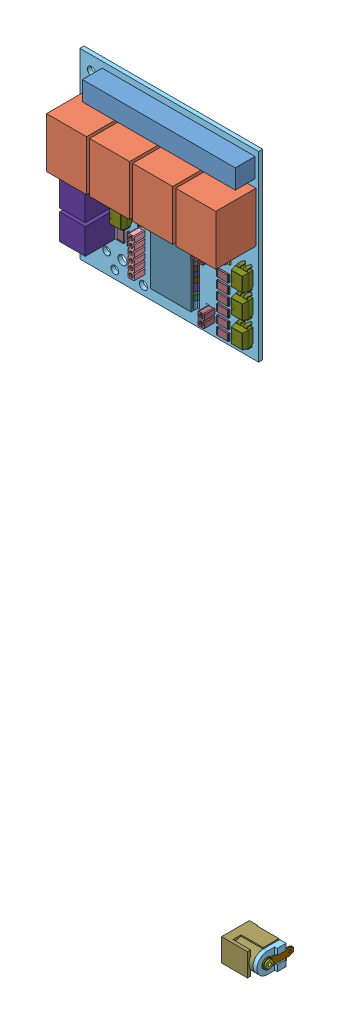
SolidWorks assembly wifi_switch, configuration Default. Lengths in mm.
Overall size (288.45 72 221.81).
193 component instances, 59 part files, 0 mates.
Components (placement in the parent):
- wifi_switch.STEP-1: wifi_switch.STEP [Default] at origin size (288.45 72 221.81)
  - 8PIN_TERMINAL.STEP-1: 8PIN_TERMINAL.STEP [Default] at (-41 33.5 0.803) size (60.33 7.62 11.71)
    - Open CASCADE STEP translator 6.8 1.2.1.STEP-1: Open CASCADE STEP translator 6.8 1.2.1.STEP [Default] at origin size (60.33 7.62 11.71)
      - Body_1.STEP-1: Body_1.STEP [Default] at origin size (60.33 7.62 7.8)
      - Pin_1.STEP-1: Pin_1.STEP [Default] x (0 -1 0) z (0 0 1) size (1.42 1.42 8.52)
      - Pin_2.STEP-1: Pin_2.STEP [Default] at (5.0038 5.0038 0) x (0 -1 0) z (0 0 1) size (1.42 1.42 8.52)
      - Pin_3.STEP-1: Pin_3.STEP [Default] at (10.0076 10.0076 0) x (0 -1 0) z (0 0 1) size (1.42 1.42 8.52)
      - Pin_4.STEP-1: Pin_4.STEP [Default] at (15.0114 15.0114 0) x (0 -1 0) z (0 0 1) size (1.42 1.42 8.52)
      - Pin_5.STEP-1: Pin_5.STEP [Default] at (19.9898 19.9898 0) x (0 -1 0) z (0 0 1) size (1.42 1.42 8.52)
      - Pin_6.STEP-1: Pin_6.STEP [Default] at (24.9936 24.9936 0) x (0 -1 0) z (0 0 1) size (1.42 1.42 8.52)
      - Pin_7.STEP-1: Pin_7.STEP [Default] at (29.9974 29.9974 0) x (0 -1 0) z (0 0 1) size (1.42 1.42 8.52)
      - Pin_8.STEP-1: Pin_8.STEP [Default] at (35.0012 35.0012 0) x (0 -1 0) z (0 0 1) size (1.42 1.42 8.52)
      - Pin_9.STEP-1: Pin_9.STEP [Default] at (40.005 40.005 0) x (0 -1 0) z (0 0 1) size (1.42 1.42 8.52)
      - Pin_10.STEP-1: Pin_10.STEP [Default] at (45.0088 45.0088 0) x (0 -1 0) z (0 0 1) size (1.42 1.42 8.52)
      - Pin_11.STEP-1: Pin_11.STEP [Default] at (50.0126 50.0126 0) x (0 -1 0) z (0 0 1) size (1.42 1.42 8.52)
      - Pin_12.STEP-1: Pin_12.STEP [Default] at (54.991 54.991 0) x (0 -1 0) z (0 0 1) size (1.42 1.42 8.52)
  - ESP.STEP-1: ESP.STEP [Default] at (-5.5 -10.5 0.803) size (18.25 24 2.16)
    - Open CASCADE STEP translator 6.8 1.3.1.STEP-1: Open CASCADE STEP translator 6.8 1.3.1.STEP [Default] at origin size (18.25 24 2.16)
      - Body_1-0.STEP-1: Body_1-0.STEP [Default] at origin size (16 24 1.91)
      - Pin_1-1.STEP-1: Pin_1-1.STEP [Default] at origin size (1.12 2.9 1.33)
      - Pin_2-2.STEP-1: Pin_2-2.STEP [Default] at origin size (1.12 2.9 1.33)
      - Pin_3-3.STEP-1: Pin_3-3.STEP [Default] at origin size (1.12 2.9 1.33)
      - Pin_4-4.STEP-1: Pin_4-4.STEP [Default] at origin size (1.12 2.9 1.33)
      - Pin_5-5.STEP-1: Pin_5-5.STEP [Default] at origin size (1.12 2.9 1.33)
      - Pin_6-6.STEP-1: Pin_6-6.STEP [Default] at origin size (1.12 2.9 1.33)
      - Pin_7-7.STEP-1: Pin_7-7.STEP [Default] at origin size (1.12 2.9 1.33)
      - Pin_8-8.STEP-1: Pin_8-8.STEP [Default] at origin size (1.12 2.9 1.33)
      - Pin_9-9.STEP-1: Pin_9-9.STEP [Default] at (0 -28 0) x (-1 0 0) z (0 0 1) size (1.13 2.9 1.33)
      - Pin_10-10.STEP-1: Pin_10-10.STEP [Default] at (0 -24 0) x (-1 0 0) z (0 0 1) size (1.13 2.9 1.33)
      - Pin_11-11.STEP-1: Pin_11-11.STEP [Default] at (0 -20 0) x (-1 0 0) z (0 0 1) size (1.13 2.9 1.33)
      - Pin_12-12.STEP-1: Pin_12-12.STEP [Default] at (0 -16 0) x (-1 0 0) z (0 0 1) size (1.13 2.9 1.33)
      - Pin_13.STEP-1: Pin_13.STEP [Default] at (0 -12 0) x (-1 0 0) z (0 0 1) size (1.13 2.9 1.33)
      - Pin_14.STEP-1: Pin_14.STEP [Default] at (0 -8 0) x (-1 0 0) z (0 0 1) size (1.13 2.9 1.33)
      - Pin_15.STEP-1: Pin_15.STEP [Default] at (0 -4 0) x (-1 0 0) z (0 0 1) size (1.13 2.9 1.33)
      - Pin_16.STEP-1: Pin_16.STEP [Default] x (-1 0 0) z (0 0 1) size (1.13 2.9 1.33)
  - R1_470.STEP-1: R1_470.STEP [Default] at (-36 -18 0.803) x (0 1 0) z (0 0 1) size (4.78 2.7 0.65)
    - Open CASCADE STEP translator 6.8 1.4.1.STEP-1: Open CASCADE STEP translator 6.8 1.4.1.STEP [Default] at origin size (4.78 2.7 0.65)
      - Body_1-13.STEP-1: Body_1-13.STEP [Default] at origin size (4.4 2.68 0.63)
      - Pin_1-14.STEP-1: Pin_1-14.STEP [Default] at (0.374 0 0) x (-1 0 0) z (0 0 1) size (0.45 2.7 0.65)
      - Pin_2-15.STEP-1: Pin_2-15.STEP [Default] at origin size (0.45 2.7 0.65)
  - R3_470.STEP-1: R3_470.STEP [Default] at (2 -9.5 0.803) size (4.78 2.7 0.65)
    - Open CASCADE STEP translator 6.8 1.4.1.STEP-1: Open CASCADE STEP translator 6.8 1.4.1.STEP [Default] at origin size (4.78 2.7 0.65)
      - Body_1-13.STEP-1: Body_1-13.STEP [Default] at origin size (4.4 2.68 0.63)
      - Pin_1-14.STEP-1: Pin_1-14.STEP [Default] at (0.374 0 0) x (-1 0 0) z (0 0 1) size (0.45 2.7 0.65)
      - Pin_2-15.STEP-1: Pin_2-15.STEP [Default] at origin size (0.45 2.7 0.65)
  - R5_470.STEP-1: R5_470.STEP [Default] at (2 -13.5 0.803) size (4.78 2.7 0.65)
    - Open CASCADE STEP translator 6.8 1.4.1.STEP-1: Open CASCADE STEP translator 6.8 1.4.1.STEP [Default] at origin size (4.78 2.7 0.65)
      - Body_1-13.STEP-1: Body_1-13.STEP [Default] at origin size (4.4 2.68 0.63)
      - Pin_1-14.STEP-1: Pin_1-14.STEP [Default] at (0.374 0 0) x (-1 0 0) z (0 0 1) size (0.45 2.7 0.65)
      - Pin_2-15.STEP-1: Pin_2-15.STEP [Default] at origin size (0.45 2.7 0.65)
  - R7_470.STEP-1: R7_470.STEP [Default] at (2 -17.5 0.803) size (4.78 2.7 0.65)
    - Open CASCADE STEP translator 6.8 1.4.1.STEP-1: Open CASCADE STEP translator 6.8 1.4.1.STEP [Default] at origin size (4.78 2.7 0.65)
      - Body_1-13.STEP-1: Body_1-13.STEP [Default] at origin size (4.4 2.68 0.63)
      - Pin_1-14.STEP-1: Pin_1-14.STEP [Default] at (0.374 0 0) x (-1 0 0) z (0 0 1) size (0.45 2.7 0.65)
      - Pin_2-15.STEP-1: Pin_2-15.STEP [Default] at origin size (0.45 2.7 0.65)
  - OP1.STEP-1: OP1.STEP [Default] at (-35.5 -11 0.803) size (5.08 7.92 7.75)
    - Open CASCADE STEP translator 6.8 1.8.1.STEP-1: Open CASCADE STEP translator 6.8 1.8.1.STEP [Default] at origin size (5.08 7.92 7.75)
      - Body_1-16.STEP-1: Body_1-16.STEP [Default] at (1.3 3.7 0) x (0 1 0) z (1 0 0) size (7.92 7.75 5.08)
  - OP2.STEP-1: OP2.STEP [Default] at (12.5 -8.5 0.803) size (5.08 7.92 7.75)
    - Open CASCADE STEP translator 6.8 1.9.1.STEP-1: Open CASCADE STEP translator 6.8 1.9.1.STEP [Default] at origin size (5.08 7.92 7.75)
      - Body_1-16.STEP-1: Body_1-16.STEP [Default] at (1.3 3.7 0) x (0 1 0) z (1 0 0) size (7.92 7.75 5.08)
  - OP3.STEP-1: OP3.STEP [Default] at (12.5 -18 0.803) size (5.08 7.92 7.75)
    - Open CASCADE STEP translator 6.8 1.10.1.STEP-1: Open CASCADE STEP translator 6.8 1.10.1.STEP [Default] at origin size (5.08 7.92 7.75)
      - Body_1-16.STEP-1: Body_1-16.STEP [Default] at (1.3 3.7 0) x (0 1 0) z (1 0 0) size (7.92 7.75 5.08)
  - OP4.STEP-1: OP4.STEP [Default] at (12.5 -28 0.803) size (5.08 7.92 7.75)
    - Open CASCADE STEP translator 6.8 1.11.1.STEP-1: Open CASCADE STEP translator 6.8 1.11.1.STEP [Default] at origin size (5.08 7.92 7.75)
      - Body_1-16.STEP-1: Body_1-16.STEP [Default] at (1.3 3.7 0) x (0 1 0) z (1 0 0) size (7.92 7.75 5.08)
  - SMPS_5V_GND.STEP-1: SMPS_5V_GND.STEP [Default] at (-43.5 -4.5 0.803) x (0 1 0) z (0 0 1) size (10.16 10.16 15.71)
    - Open CASCADE STEP translator 6.8 1.12.1.STEP-1: Open CASCADE STEP translator 6.8 1.12.1.STEP [Default] at origin size (10.16 10.16 15.71)
      - Body_1-17.STEP-1: Body_1-17.STEP [Default] at origin size (10.16 10.16 11.8)
      - Pin_1-18.STEP-1: Pin_1-18.STEP [Default] x (0 -1 0) z (0 0 1) size (1.42 1.42 10.52)
      - Pin_2-19.STEP-1: Pin_2-19.STEP [Default] at (5.08 5.08 0) x (0 -1 0) z (0 0 1) size (1.42 1.42 10.52)
  - SMPS_L_N.STEP-1: SMPS_L_N.STEP [Default] at (-43.5 -16 0.803) x (0 1 0) z (0 0 1) size (10.16 10.16 15.71)
    - Open CASCADE STEP translator 6.8 1.12.1.STEP-1: Open CASCADE STEP translator 6.8 1.12.1.STEP [Default] at origin size (10.16 10.16 15.71)
      - Body_1-17.STEP-1: Body_1-17.STEP [Default] at origin size (10.16 10.16 11.8)
      - Pin_1-18.STEP-1: Pin_1-18.STEP [Default] x (0 -1 0) z (0 0 1) size (1.42 1.42 10.52)
      - Pin_2-19.STEP-1: Pin_2-19.STEP [Default] at (5.08 5.08 0) x (0 -1 0) z (0 0 1) size (1.42 1.42 10.52)
  - RL4.STEP-1: RL4.STEP [Default] at (-31 10 0.803) x (0 1 0) z (0 0 1) size (19.8 15.8 19.1)
    - Open CASCADE STEP translator 6.8 1.14.1.STEP-1: Open CASCADE STEP translator 6.8 1.14.1.STEP [Default] at origin size (19.8 15.8 19.1)
      - Body_1-20.STEP-1: Body_1-20.STEP [Default] at (6.5 -6 0) x (1 0 0) z (0 -1 0) size (19.8 19.1 15.8)
        - 1.STEP-1: 1.STEP [Default] at origin size (19.8 19.1 15.8)
        - 2.STEP-1: 2.STEP [Default] at origin size (1 4 0.4)
  - RL1.STEP-1: RL1.STEP [Default] at (-48 10 0.803) x (0 1 0) z (0 0 1) size (19.8 15.8 19.1)
    - Open CASCADE STEP translator 6.8 1.15.1.STEP-1: Open CASCADE STEP translator 6.8 1.15.1.STEP [Default] at origin size (19.8 15.8 19.1)
      - Body_1-1.STEP-1: Body_1-1.STEP [Default] at (6.5 -6 0) x (1 0 0) z (0 -1 0) size (19.8 19.1 15.8)
        - 1.STEP-1: 1.STEP [Default] at origin size (19.8 19.1 15.8)
        - 2.STEP-1: 2.STEP [Default] at origin size (1 4 0.4)
  - RL2.STEP-1: RL2.STEP [Default] at (-14 10 0.803) x (0 1 0) z (0 0 1) size (19.8 15.8 19.1)
    - Open CASCADE STEP translator 6.8 1.16.1.STEP-1: Open CASCADE STEP translator 6.8 1.16.1.STEP [Default] at origin size (19.8 15.8 19.1)
      - Body_1-2.STEP-1: Body_1-2.STEP [Default] at (6.5 -6 0) x (1 0 0) z (0 -1 0) size (19.8 19.1 15.8)
        - 1.STEP-1: 1.STEP [Default] at origin size (19.8 19.1 15.8)
        - 2.STEP-1: 2.STEP [Default] at origin size (1 4 0.4)
  - RL3.STEP-1: RL3.STEP [Default] at (3 10 0.803) x (0 1 0) z (0 0 1) size (19.8 15.8 19.1)
    - Open CASCADE STEP translator 6.8 1.17.1.STEP-1: Open CASCADE STEP translator 6.8 1.17.1.STEP [Default] at origin size (19.8 15.8 19.1)
      - Body_1-3.STEP-1: Body_1-3.STEP [Default] at (6.5 -6 0) x (1 0 0) z (0 -1 0) size (19.8 19.1 15.8)
        - 1.STEP-1: 1.STEP [Default] at origin size (19.8 19.1 15.8)
        - 2.STEP-1: 2.STEP [Default] at origin size (1 4 0.4)
  - DISPLAY_CONNECTOR.STEP-1: DISPLAY_CONNECTOR.STEP [Default] at (0 0 0.803) size (10.16 2.54 7.37)
    - Open CASCADE STEP translator 6.8 1.18.1.STEP-1: Open CASCADE STEP translator 6.8 1.18.1.STEP [Default] at origin size (10.16 2.54 7.37)
      - Body_1-21.STEP-1: Body_1-21.STEP [Default] at (3.8 0 0) x (1 0 0) z (0 -1 0) size (10.16 7.37 2.54)
  - DC_JACK.STEP-1: DC_JACK.STEP [Default] at (-42 -24.5 0.803) x (0 -1 0) z (0 0 1) size (9.5 14.51 14.4)
    - Open CASCADE STEP translator 6.8 1.19.1.STEP-1: Open CASCADE STEP translator 6.8 1.19.1.STEP [Default] at origin size (9.5 14.51 14.4)
      - Body_1-4.STEP-1: Body_1-4.STEP [Default] at (-1.97 277.95 212.6) x (-1 0 0) z (0 1 0) size (9.5 14.4 14.51)
        - =_[0_1_1_3].STEP-1: =_[0_1_1_3].STEP [Default] at origin size (8 10.5 2.55)
        - =_[0_1_1_4].STEP-1: =_[0_1_1_4].STEP [Default] at origin size (1.93 1.93 11.95)
        - =_[0_1_1_5].STEP-1: =_[0_1_1_5].STEP [Default] at origin size (3.3 3.3 1)
        - =_[0_1_1_6].STEP-1: =_[0_1_1_6].STEP [Default] at origin size (1.5 7.4 7.5)
        - =_[0_1_1_7].STEP-1: =_[0_1_1_7].STEP [Default] at origin size (4 12 0.5)
        - =_[0_1_1_8].STEP-1: =_[0_1_1_8].STEP [Default] at origin size (3.5 3.5 0.2)
        - =_[0_1_1_9].STEP-1: =_[0_1_1_9].STEP [Default] at origin size (2.5 3.7 0.2)
        - =_[0_1_1_10].STEP-1: =_[0_1_1_10].STEP [Default] at origin size (9 11 11.96)
  - RX.STEP-1: RX.STEP [Default] at (-3.5 -5 0.803) size (5.08 2.54 7.37)
    - Open CASCADE STEP translator 6.8 1.20.1.STEP-1: Open CASCADE STEP translator 6.8 1.20.1.STEP [Default] at origin size (5.08 2.54 7.37)
      - Body_1-22.STEP-1: Body_1-22.STEP [Default] at (1.3 0 0) x (1 0 0) z (0 -1 0) size (5.08 7.37 2.54)
  - Q1.STEP-1: Q1.STEP [Default] at (-34 1 0.803) size (4.8 20.44 3.83)
    - Open CASCADE STEP translator 6.8 1.21.1.STEP-1: Open CASCADE STEP translator 6.8 1.21.1.STEP [Default] at origin size (4.8 20.44 3.83)
      - Body_1-5.STEP-1: Body_1-5.STEP [Default] at origin size (4.8 20.44 3.83)
        - =_[0_1_1_3]-23.STEP-1: =_[0_1_1_3]-23.STEP [Default] at origin size (0.48 15.53 0.43)
        - =_[0_1_1_4]-24.STEP-1: =_[0_1_1_4]-24.STEP [Default] at origin size (0.49 15.53 0.43)
        - =_[0_1_1_5]-25.STEP-1: =_[0_1_1_5]-25.STEP [Default] at origin size (0.48 15.53 0.43)
        - =_[0_1_1_6]-26.STEP-1: =_[0_1_1_6]-26.STEP [Default] at origin size (4.8 4.95 3.83)
        - =_[0_1_1_7]-27.STEP-1: =_[0_1_1_7]-27.STEP [Default] at origin size (0.7 0.7 0.05)
  - Q2.STEP-1: Q2.STEP [Default] at (-10 1 0.803) size (4.8 20.44 3.83)
    - Open CASCADE STEP translator 6.8 1.22.1.STEP-1: Open CASCADE STEP translator 6.8 1.22.1.STEP [Default] at origin size (4.8 20.44 3.83)
      - Body_1-5.STEP-1: Body_1-5.STEP [Default] at origin size (4.8 20.44 3.83)
        - =_[0_1_1_3]-23.STEP-1: =_[0_1_1_3]-23.STEP [Default] at origin size (0.48 15.53 0.43)
        - =_[0_1_1_4]-24.STEP-1: =_[0_1_1_4]-24.STEP [Default] at origin size (0.49 15.53 0.43)
        - =_[0_1_1_5]-25.STEP-1: =_[0_1_1_5]-25.STEP [Default] at origin size (0.48 15.53 0.43)
        - =_[0_1_1_6]-26.STEP-1: =_[0_1_1_6]-26.STEP [Default] at origin size (4.8 4.95 3.83)
        - =_[0_1_1_7]-27.STEP-1: =_[0_1_1_7]-27.STEP [Default] at origin size (0.7 0.7 0.05)
  - Q3.STEP-1: Q3.STEP [Default] at (-16.5 1 0.803) size (4.8 20.44 3.83)
    - Open CASCADE STEP translator 6.8 1.23.1.STEP-1: Open CASCADE STEP translator 6.8 1.23.1.STEP [Default] at origin size (4.8 20.44 3.83)
      - Body_1-5.STEP-1: Body_1-5.STEP [Default] at origin size (4.8 20.44 3.83)
        - =_[0_1_1_3]-23.STEP-1: =_[0_1_1_3]-23.STEP [Default] at origin size (0.48 15.53 0.43)
        - =_[0_1_1_4]-24.STEP-1: =_[0_1_1_4]-24.STEP [Default] at origin size (0.49 15.53 0.43)
        - =_[0_1_1_5]-25.STEP-1: =_[0_1_1_5]-25.STEP [Default] at origin size (0.48 15.53 0.43)
        - =_[0_1_1_6]-26.STEP-1: =_[0_1_1_6]-26.STEP [Default] at origin size (4.8 4.95 3.83)
        - =_[0_1_1_7]-27.STEP-1: =_[0_1_1_7]-27.STEP [Default] at origin size (0.7 0.7 0.05)
  - Q4.STEP-1: Q4.STEP [Default] at (-22.5 1 0.803) size (4.8 20.44 3.83)
    - Open CASCADE STEP translator 6.8 1.24.1.STEP-1: Open CASCADE STEP translator 6.8 1.24.1.STEP [Default] at origin size (4.8 20.44 3.83)
      - Body_1-5.STEP-1: Body_1-5.STEP [Default] at origin size (4.8 20.44 3.83)
        - =_[0_1_1_3]-23.STEP-1: =_[0_1_1_3]-23.STEP [Default] at origin size (0.48 15.53 0.43)
        - =_[0_1_1_4]-24.STEP-1: =_[0_1_1_4]-24.STEP [Default] at origin size (0.49 15.53 0.43)
        - =_[0_1_1_5]-25.STEP-1: =_[0_1_1_5]-25.STEP [Default] at origin size (0.48 15.53 0.43)
        - =_[0_1_1_6]-26.STEP-1: =_[0_1_1_6]-26.STEP [Default] at origin size (4.8 4.95 3.83)
        - =_[0_1_1_7]-27.STEP-1: =_[0_1_1_7]-27.STEP [Default] at origin size (0.7 0.7 0.05)
  - R2_120.STEP-1: R2_120.STEP [Default] at (-32 -18 0.803) x (0 1 0) z (0 0 1) size (4.78 2.7 0.65)
    - Open CASCADE STEP translator 6.8 1.4.1.STEP-1: Open CASCADE STEP translator 6.8 1.4.1.STEP [Default] at origin size (4.78 2.7 0.65)
      - Body_1-13.STEP-1: Body_1-13.STEP [Default] at origin size (4.4 2.68 0.63)
      - Pin_1-14.STEP-1: Pin_1-14.STEP [Default] at (0.374 0 0) x (-1 0 0) z (0 0 1) size (0.45 2.7 0.65)
      - Pin_2-15.STEP-1: Pin_2-15.STEP [Default] at origin size (0.45 2.7 0.65)
  - R4_120.STEP-1: R4_120.STEP [Default] at (2 -21.5 0.803) size (4.78 2.7 0.65)
    - Open CASCADE STEP translator 6.8 1.4.1.STEP-1: Open CASCADE STEP translator 6.8 1.4.1.STEP [Default] at origin size (4.78 2.7 0.65)
      - Body_1-13.STEP-1: Body_1-13.STEP [Default] at origin size (4.4 2.68 0.63)
      - Pin_1-14.STEP-1: Pin_1-14.STEP [Default] at (0.374 0 0) x (-1 0 0) z (0 0 1) size (0.45 2.7 0.65)
      - Pin_2-15.STEP-1: Pin_2-15.STEP [Default] at origin size (0.45 2.7 0.65)
  - R6_120.STEP-1: R6_120.STEP [Default] at (2 -25.5 0.803) size (4.78 2.7 0.65)
    - Open CASCADE STEP translator 6.8 1.4.1.STEP-1: Open CASCADE STEP translator 6.8 1.4.1.STEP [Default] at origin size (4.78 2.7 0.65)
      - Body_1-13.STEP-1: Body_1-13.STEP [Default] at origin size (4.4 2.68 0.63)
      - Pin_1-14.STEP-1: Pin_1-14.STEP [Default] at (0.374 0 0) x (-1 0 0) z (0 0 1) size (0.45 2.7 0.65)
      - Pin_2-15.STEP-1: Pin_2-15.STEP [Default] at origin size (0.45 2.7 0.65)
  - R8_120.STEP-1: R8_120.STEP [Default] at (2 -29.5 0.803) size (4.78 2.7 0.65)
    - Open CASCADE STEP translator 6.8 1.4.1.STEP-1: Open CASCADE STEP translator 6.8 1.4.1.STEP [Default] at origin size (4.78 2.7 0.65)
      - Body_1-13.STEP-1: Body_1-13.STEP [Default] at origin size (4.4 2.68 0.63)
      - Pin_1-14.STEP-1: Pin_1-14.STEP [Default] at (0.374 0 0) x (-1 0 0) z (0 0 1) size (0.45 2.7 0.65)
      - Pin_2-15.STEP-1: Pin_2-15.STEP [Default] at origin size (0.45 2.7 0.65)
  - PN1.STEP-1: PN1.STEP [Default] at (-28.5 1 0.803) size (3.05 1.5 2.16)
    - Open CASCADE STEP translator 6.8 1.29.1.STEP-1: Open CASCADE STEP translator 6.8 1.29.1.STEP [Default] at origin size (3.05 1.5 2.16)
      - Body_1-28.STEP-1: Body_1-28.STEP [Default] at origin size (0.4 0.8 1.91)
      - Pin_1-29.STEP-1: Pin_1-29.STEP [Default] at origin size (1.32 1.5 1.33)
      - Pin_2-30.STEP-1: Pin_2-30.STEP [Default] at (2.8 0 0) x (-1 0 0) z (0 0 1) size (1.32 1.5 1.33)
  - PN2.STEP-1: PN2.STEP [Default] at (-27.5 -3 0.803) size (3.05 1.5 2.16)
    - Open CASCADE STEP translator 6.8 1.29.1.STEP-1: Open CASCADE STEP translator 6.8 1.29.1.STEP [Default] at origin size (3.05 1.5 2.16)
      - Body_1-28.STEP-1: Body_1-28.STEP [Default] at origin size (0.4 0.8 1.91)
      - Pin_1-29.STEP-1: Pin_1-29.STEP [Default] at origin size (1.32 1.5 1.33)
      - Pin_2-30.STEP-1: Pin_2-30.STEP [Default] at (2.8 0 0) x (-1 0 0) z (0 0 1) size (1.32 1.5 1.33)
  - PN3.STEP-1: PN3.STEP [Default] at (-27.5 -7.5 0.803) size (3.05 1.5 2.16)
    - Open CASCADE STEP translator 6.8 1.29.1.STEP-1: Open CASCADE STEP translator 6.8 1.29.1.STEP [Default] at origin size (3.05 1.5 2.16)
      - Body_1-28.STEP-1: Body_1-28.STEP [Default] at origin size (0.4 0.8 1.91)
      - Pin_1-29.STEP-1: Pin_1-29.STEP [Default] at origin size (1.32 1.5 1.33)
      - Pin_2-30.STEP-1: Pin_2-30.STEP [Default] at (2.8 0 0) x (-1 0 0) z (0 0 1) size (1.32 1.5 1.33)
  - PN4.STEP-1: PN4.STEP [Default] at (5.5 -4 0.803) size (3.05 1.5 2.16)
    - Open CASCADE STEP translator 6.8 1.29.1.STEP-1: Open CASCADE STEP translator 6.8 1.29.1.STEP [Default] at origin size (3.05 1.5 2.16)
      - Body_1-28.STEP-1: Body_1-28.STEP [Default] at origin size (0.4 0.8 1.91)
      - Pin_1-29.STEP-1: Pin_1-29.STEP [Default] at origin size (1.32 1.5 1.33)
      - Pin_2-30.STEP-1: Pin_2-30.STEP [Default] at (2.8 0 0) x (-1 0 0) z (0 0 1) size (1.32 1.5 1.33)
  - PROG.STEP-1: PROG.STEP [Default] at (-28.103 -24 0.803) x (0 1 0) z (0 0 1) size (15.24 2.54 7.37)
    - Open CASCADE STEP translator 6.8 1.33.1.STEP-1: Open CASCADE STEP translator 6.8 1.33.1.STEP [Default] at origin size (15.24 2.54 7.37)
      - Body_1-31.STEP-1: Body_1-31.STEP [Default] at (6.5 0 0) x (1 0 0) z (0 -1 0) size (15.24 7.37 2.54)
  - RESET.STEP-1: RESET.STEP [Default] at (-0.5 -26.5 0.803) x (0 1 0) z (0 0 1) size (5.08 2.54 7.37)
    - Open CASCADE STEP translator 6.8 1.34.1.STEP-1: Open CASCADE STEP translator 6.8 1.34.1.STEP [Default] at origin size (5.08 2.54 7.37)
      - Body_1-22.STEP-1: Body_1-22.STEP [Default] at (1.3 0 0) x (1 0 0) z (0 -1 0) size (5.08 7.37 2.54)
  - Layer_1.STEP-1: Layer_1.STEP [Default] at origin size (70.5 72 1.61)
